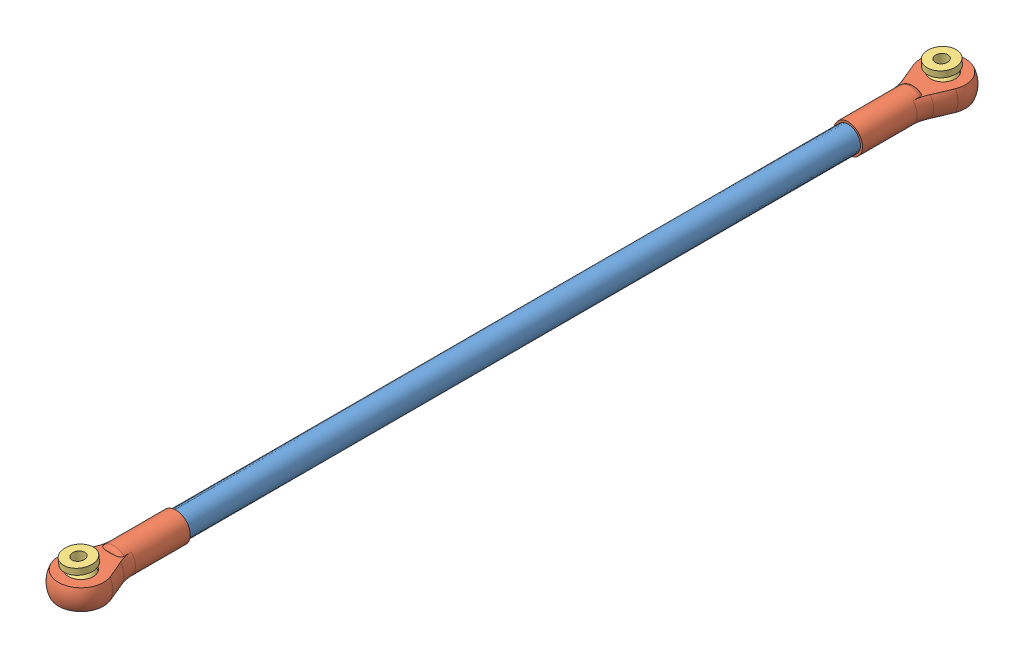
SolidWorks assembly Bar_3, configuration Default. Lengths in mm.
Overall size (12 9.77 221).
5 component instances, 3 part files, 8 mates.
Components (placement in the parent):
- Bar_3-1: Bar_3 [Default] at origin size (6 6 191)
- Ball_socket-1: Ball_socket [Default] at (0 0 -1) x (0 -1 0) z (0 0 1) size (7 12 29)
- Ball_socket-2: Ball_socket [Default] at (0 0 192) x (0 1 0) z (0 0 -1) size (7 12 29)
- Ball_2-1: Ball_2 [Default] at (0.0404 -3.6227 -9.186) x (0.967541 -0.002193 0.252705) z (0.011132 -0.998622 -0.051285) size (7 7 9)
- Ball_2-2: Ball_2 [Default] at (0.162 -3.6156 199.7515) x (0.996862 0.048944 -0.062207) z (0.044659 -0.996651 -0.068501) size (7 7 9)
Mates (geometry in assembly coordinates):
- Concentric1: concentric aligned: cylinder of Bar_3-1 through (0 0 191) axis (0 0 -1) radius 3; cylinder of Ball_socket-1 through (0 0 14) axis (0 0 -1) radius 3
- Concentric2: concentric anti-aligned: cylinder of Bar_3-1 through (0 0 191) axis (0 0 -1) radius 3; cylinder of Ball_socket-2 through (0 0 177) axis (0 0 1) radius 3
- Parallel1: parallel aligned: plane of Ball_socket-1 through (-17.5 -2.5 -1) normal (0 -1 0); plane of Ball_socket-2 through (-17.5 -2.5 192) normal (0 -1 0)
- Parallel2: parallel anti-aligned: plane of Ball_socket-2 through (-17.5 -2.5 192) normal (0 -1 0); plane of assembly through (0 0 0) normal (0 1 0)
- Coincident3: coincident anti-aligned: plane of Bar_3-1 through (0 0 0) normal (0 0 -1); plane of Ball_socket-1 through (0 0 0) normal (0 0 1)
- Coincident4: coincident anti-aligned: plane of Bar_3-1 through (0 0 191) normal (0 0 1); plane of Ball_socket-2 through (0 0 191) normal (0 0 -1)
- Concentric3: concentric: sphere of Ball_socket-2; sphere of Ball_2-2
- Concentric4: concentric: sphere of Ball_socket-1; sphere of Ball_2-1
